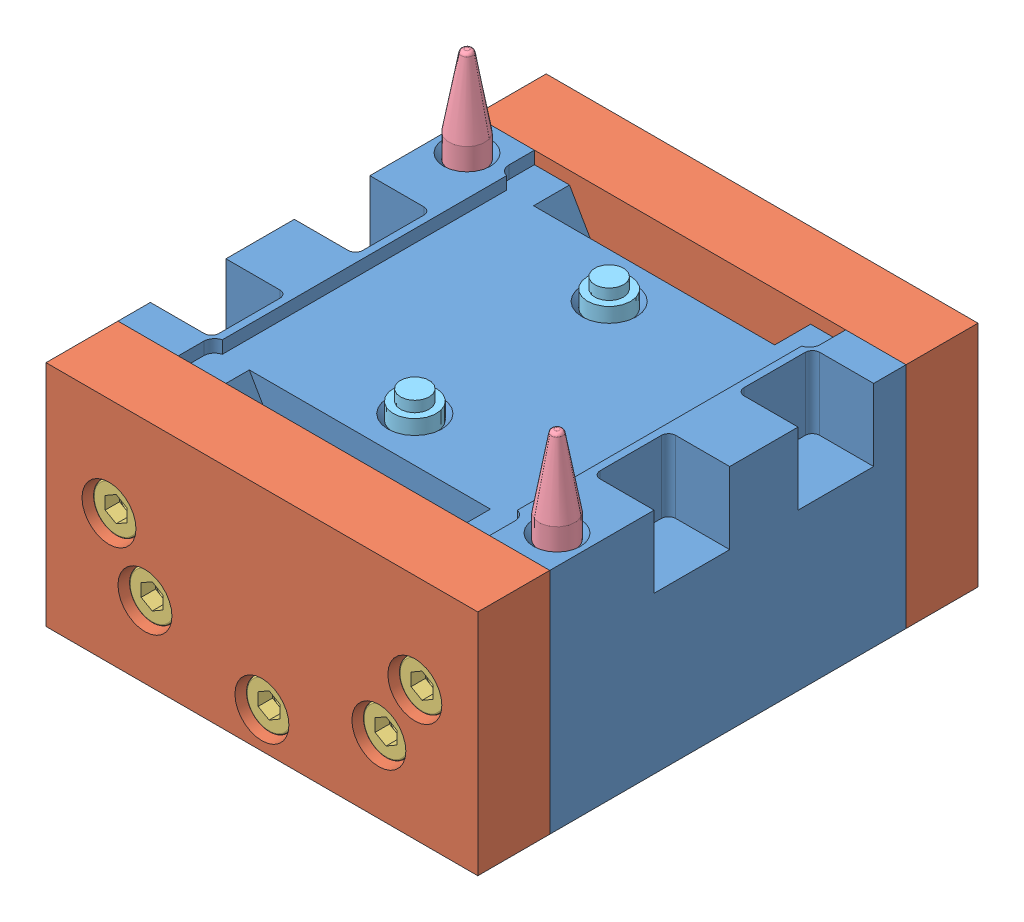
SolidWorks assembly Сборка1, configuration По умолчанию. Lengths in mm.
Overall size (120 88.5 139).
19 component instances, 5 part files, 34 mates.
Components (placement in the parent):
- Матрица-1: Матрица [Default] at origin size (120 63.5 99)
- Боковина Пресс-формы.-1: Боковина Пресс-формы. [По умолчанию] at (0 36.1757 49.5) size (120 63.5 20)
- Боковина Пресс-формы.-3: Боковина Пресс-формы. [По умолчанию] at (0 36.1757 -49.5) x (-1 0 0) z (0 0 -1) size (120 63.5 20)
- socket head cap screw_iso-1: socket head cap screw_iso [ISO 4762 M8 x 16 - 16N] at (-42.5 36 -67.5) x (0 0 1) z (-1 0 0) size (24 13 13)
- socket head cap screw_iso-2: socket head cap screw_iso [ISO 4762 M8 x 16 - 16N] at (-32.5 20 -67.5) x (0 0 1) z (-1 0 0) size (24 13 13)
- socket head cap screw_iso-3: socket head cap screw_iso [ISO 4762 M8 x 16 - 16N] at (0 10 -67.5) x (0 0 1) z (-1 0 0) size (24 13 13)
- socket head cap screw_iso-4: socket head cap screw_iso [ISO 4762 M8 x 16 - 16N] at (32.5 20 -67.5) x (0 0 1) z (-1 0 0) size (24 13 13)
- socket head cap screw_iso-5: socket head cap screw_iso [ISO 4762 M8 x 16 - 16N] at (42.5 36 -67.5) x (0 0 1) z (-1 0 0) size (24 13 13)
- socket head cap screw_iso-6: socket head cap screw_iso [ISO 4762 M8 x 16 - 16N] at (42.5 36 67.5) x (0 0 -1) z (1 0 0) size (24 13 13)
- socket head cap screw_iso-7: socket head cap screw_iso [ISO 4762 M8 x 16 - 16N] at (32.5 20 67.5) x (0 0 -1) z (1 0 0) size (24 13 13)
- socket head cap screw_iso-10: socket head cap screw_iso [ISO 4762 M8 x 16 - 16N] at (-42.5 36 67.5) x (0 0 -1) z (1 0 0) size (24 13 13)
- socket head cap screw_iso-8: socket head cap screw_iso [ISO 4762 M8 x 16 - 16N] at (0 10 67.5) x (0 0 -1) z (1 0 0) size (24 13 13)
- socket head cap screw_iso-9: socket head cap screw_iso [ISO 4762 M8 x 16 - 16N] at (-32.5 20 67.5) x (0 0 -1) z (1 0 0) size (24 13 13)
- socket head cap screw_iso-11: socket head cap screw_iso [ISO 4762 M8 x 16 - 16N] at (-32.5 20 67.5) x (0 0 -1) z (1 0 0) size (24 13 13)
- socket head cap screw_iso-12: socket head cap screw_iso [ISO 4762 M8 x 16 - 16N] at (-42.5 36 67.5) x (0 0 -1) z (1 0 0) size (24 13 13)
- Направляющая-1: Направляющая [Default] at (52 33.5 39.5) x (0 1 0) z (-0.458497 0 -0.888696) size (55 10 10)
- Направляющая-3: Направляющая [Default] at (-52 33.5 -39.5) x (0 1 0) z (-0.61776 0 -0.786366) size (55 10 10)
- Подставка-2: Подставка [По умолчанию] at (0 48 -27) x (0.955678 0 -0.294415) z (0 -1 0) size (12 12 36)
- Подставка-3: Подставка [По умолчанию] at (0 48 27) x (0.972927 0 -0.231111) z (0 -1 0) size (12 12 36)
Mates (geometry in assembly coordinates):
- Совпадение1: coincident anti-aligned: plane of Матрица-1 through (60 63.5 49.5) normal (0 0 1); plane of Боковина Пресс-формы.-1 through (0 36.1757 49.5) normal (0 0 -1)
- Концентричный1: concentric anti-aligned: cylinder of Матрица-1 through (42.5 36 49.5) axis (0 0 1) radius 3.5; cylinder of Боковина Пресс-формы.-1 through (42.5 36 69.5) axis (0 0 -1) radius 4.25
- Концентричный2: concentric anti-aligned: cylinder of Матрица-1 through (-42.5 36 49.5) axis (0 0 1) radius 3.5; cylinder of Боковина Пресс-формы.-1 through (-42.5 36 69.5) axis (0 0 -1) radius 4.25
- Совпадение3: coincident anti-aligned: plane of Матрица-1 through (60 63.5 -49.5) normal (0 0 -1); plane of Боковина Пресс-формы.-3 through (0 36.1757 -49.5) normal (0 0 1)
- Концентричный3: concentric anti-aligned: cylinder of Матрица-1 through (42.5 36 -49.5) axis (0 0 -1) radius 3.5; cylinder of Боковина Пресс-формы.-3 through (42.5 36 -69.5) axis (0 0 1) radius 4.25
- Концентричный4: concentric anti-aligned: cylinder of Матрица-1 through (-42.5 36 -49.5) axis (0 0 -1) radius 3.5; cylinder of Боковина Пресс-формы.-3 through (-42.5 36 -69.5) axis (0 0 1) radius 4.25
- Концентричный5: concentric anti-aligned: cylinder of Боковина Пресс-формы.-3 through (-42.5 36 -69.5) axis (0 0 1) radius 4.25; cylinder of socket head cap screw_iso-1 through (-42.5 36 -99.25) axis (0 0 -1) radius 6.5
- Совпадение4: coincident anti-aligned: plane of Боковина Пресс-формы.-3 through (-42.5 36 -59.5) normal (0 0 -1); plane of socket head cap screw_iso-1 through (-42.5 42.5 -59.5) normal (0 0 1)
- Концентричный6: concentric aligned: cylinder of Боковина Пресс-формы.-3 through (-32.5 20 -59.5) axis (0 0 -1) radius 7.5; cylinder of socket head cap screw_iso-2 through (-32.5 20 -99.25) axis (0 0 -1) radius 6.5
- Совпадение5: coincident anti-aligned: plane of Боковина Пресс-формы.-3 through (-32.5 20 -59.5) normal (0 0 -1); plane of socket head cap screw_iso-2 through (-32.5 26.5 -59.5) normal (0 0 1)
- Концентричный7: concentric anti-aligned: cylinder of Боковина Пресс-формы.-3 through (0 10 -69.5) axis (0 0 1) radius 4.25; cylinder of socket head cap screw_iso-3 through (0 10 -99.25) axis (0 0 -1) radius 6.5
- Совпадение6: coincident anti-aligned: plane of Боковина Пресс-формы.-3 through (0 10 -59.5) normal (0 0 -1); plane of socket head cap screw_iso-3 through (0 16.5 -59.5) normal (0 0 1)
- Концентричный8: concentric anti-aligned: cylinder of Боковина Пресс-формы.-3 through (32.5 20 -69.5) axis (0 0 1) radius 4.25; cylinder of socket head cap screw_iso-4 through (32.5 20 -99.25) axis (0 0 -1) radius 6.5
- Совпадение7: coincident anti-aligned: plane of Боковина Пресс-формы.-3 through (32.5 20 -59.5) normal (0 0 -1); plane of socket head cap screw_iso-4 through (32.5 26.5 -59.5) normal (0 0 1)
- Концентричный9: concentric aligned: cylinder of Боковина Пресс-формы.-3 through (42.5 36 -59.5) axis (0 0 -1) radius 7.5; cylinder of socket head cap screw_iso-5 through (42.5 36 -99.25) axis (0 0 -1) radius 6.5
- Совпадение8: coincident anti-aligned: plane of Боковина Пресс-формы.-3 through (42.5 36 -59.5) normal (0 0 -1); plane of socket head cap screw_iso-5 through (42.5 42.5 -59.5) normal (0 0 1)
- Концентричный10: concentric anti-aligned: cylinder of Боковина Пресс-формы.-1 through (42.5 36 69.5) axis (0 0 -1) radius 4.25; cylinder of socket head cap screw_iso-6 through (42.5 36 99.25) axis (0 0 1) radius 6.5
- Совпадение9: coincident anti-aligned: plane of Боковина Пресс-формы.-1 through (42.5 36 59.5) normal (0 0 1); plane of socket head cap screw_iso-6 through (42.5 42.5 59.5) normal (0 0 -1)
- Концентричный11: concentric aligned: cylinder of Боковина Пресс-формы.-1 through (32.5 20 59.5) axis (0 0 1) radius 7.5; cylinder of socket head cap screw_iso-7 through (32.5 20 99.25) axis (0 0 1) radius 6.5
- Совпадение10: coincident anti-aligned: plane of Боковина Пресс-формы.-1 through (32.5 20 59.5) normal (0 0 1); plane of socket head cap screw_iso-7 through (32.5 26.5 59.5) normal (0 0 -1)
- Концентричный12: concentric anti-aligned: cylinder of Боковина Пресс-формы.-1 through (0 10 69.5) axis (0 0 -1) radius 4.25; cylinder of socket head cap screw_iso-8 through (0 10 99.25) axis (0 0 1) radius 6.5
- Совпадение11: coincident anti-aligned: plane of Боковина Пресс-формы.-1 through (0 10 59.5) normal (0 0 1); plane of socket head cap screw_iso-8 through (0 16.5 59.5) normal (0 0 -1)
- Концентричный13: concentric aligned: cylinder of Боковина Пресс-формы.-1 through (-32.5 20 59.5) axis (0 0 1) radius 7.5; cylinder of socket head cap screw_iso-9 through (-32.5 20 99.25) axis (0 0 1) radius 6.5
- Совпадение12: coincident anti-aligned: plane of Боковина Пресс-формы.-1 through (-32.5 20 59.5) normal (0 0 1); plane of socket head cap screw_iso-9 through (-32.5 26.5 59.5) normal (0 0 -1)
- Концентричный14: concentric aligned: cylinder of Боковина Пресс-формы.-1 through (-42.5 36 59.5) axis (0 0 1) radius 7.5; cylinder of socket head cap screw_iso-10 through (-42.5 36 99.25) axis (0 0 1) radius 6.5
- Совпадение13: coincident anti-aligned: plane of Боковина Пресс-формы.-1 through (-42.5 36 59.5) normal (0 0 1); plane of socket head cap screw_iso-10 through (-42.5 42.5 59.5) normal (0 0 -1)
- Концентричный15: concentric anti-aligned: cylinder of Матрица-1 through (52 33.5 39.5) axis (0 1 0) radius 5; cylinder of Направляющая-1 through (52 33.5 39.5) axis (0 -1 0) radius 5
- Совпадение14: coincident anti-aligned: plane of Матрица-1 through (52 33.5 39.5) normal (0 1 0); circle of Направляющая-1
- Концентричный17: concentric anti-aligned: cylinder of Матрица-1 through (-52 33.5 -39.5) axis (0 1 0) radius 5; cylinder of Направляющая-3 through (-52 33.5 -39.5) axis (0 -1 0) radius 5
- Совпадение17: coincident anti-aligned: plane of Матрица-1 through (-52 33.5 -39.5) normal (0 1 0); circle of Направляющая-3
- Концентричный20: concentric anti-aligned: cylinder of Матрица-1 through (0 30 -27) axis (0 1 0) radius 6; cylinder of Подставка-2 through (0 30 -27) axis (0 -1 0) radius 6
- Концентричный21: concentric anti-aligned: cylinder of Матрица-1 through (0 30 27) axis (0 1 0) radius 6; cylinder of Подставка-3 through (0 30 27) axis (0 -1 0) radius 6
- Совпадение20: coincident anti-aligned: plane of Матрица-1 through (0 30 0) normal (0 1 0); plane of Подставка-3 through (0 30 27) normal (0 -1 0)
- Совпадение21: coincident anti-aligned: plane of Матрица-1 through (0 30 0) normal (0 1 0); plane of Подставка-2 through (0 30 -27) normal (0 -1 0)
